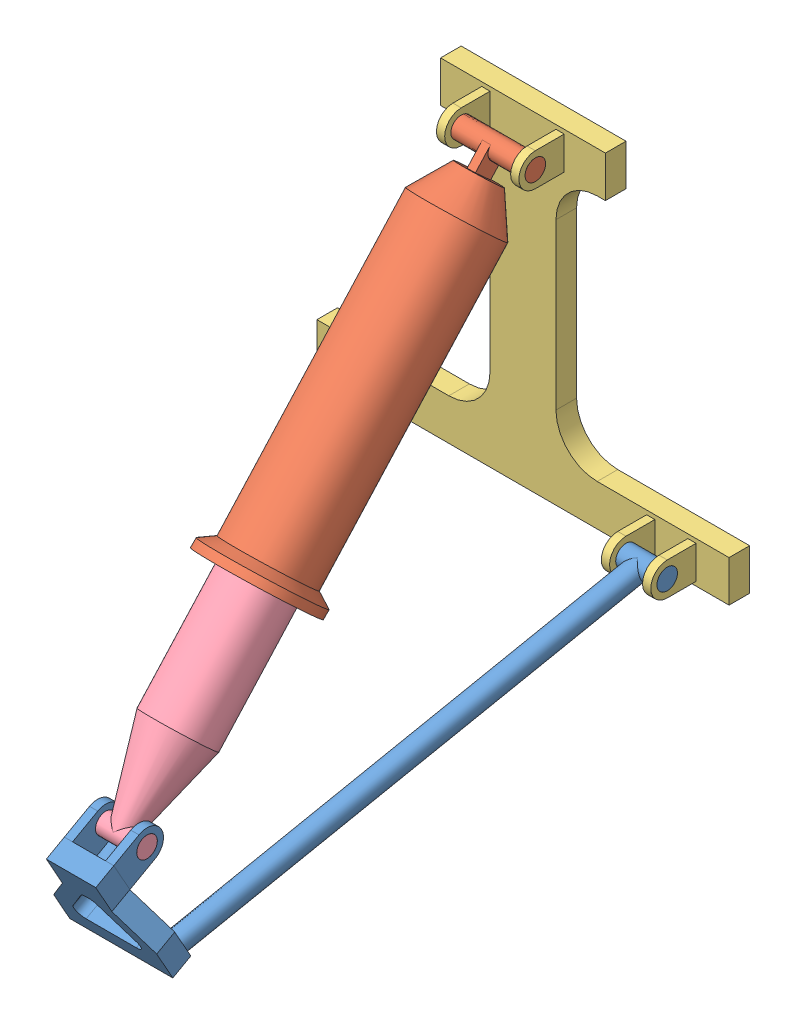
SolidWorks assembly Assembly2_SmithF, configuration 1. Lengths in mm.
Overall size (100 133.96 114.65).
4 component instances, 4 part files, 9 mates.
Components (placement in the parent):
- A-Arm-1: A-Arm [Default<As Machined>] at (0 5 12) x (1 0 0) z (0 -0.487404 0.873176) size (84 25 107.5)
- Cylinder-1: Cylinder [Default] at (0 11.7553 69.5357) x (1 0 0) z (0 0.672932 0.739705) size (26 88 26)
- Mount-1: Mount [Default] at origin size (100 80 16)
- Piston-1: Piston [Default] at (0 12.8104 68.5758) x (1 0 0) z (0 -0.739705 0.672932) size (16 16 102.5)
Mates (geometry in assembly coordinates):
- Coincident1: coordinate: point of Mount-1
- Concentric1: concentric anti-aligned: cylinder of Cylinder-1 through (13 75 12) axis (-1 0 0) radius 2.5; cylinder of Mount-1 through (-50 75 12) axis (1 0 0) radius 2.5
- Coincident2: coincident aligned: plane of Cylinder-1 through (10 11.7553 69.5357) normal (1 0 0); plane of Mount-1 through (10 79 17) normal (1 0 0)
- Concentric2: concentric anti-aligned: cylinder of Cylinder-1 through (0 70.9316 15.7011) axis (0 0.739705 -0.672932) radius 8; cylinder of Piston-1 through (0 -24.1748 102.2224) axis (0 -0.739705 0.672932) radius 8
- Parallel1: parallel aligned: plane of Cylinder-1 through (10 11.7553 69.5357) normal (1 0 0); plane of Piston-1 through (6 -24.1748 102.2224) normal (1 0 0)
- Concentric3: concentric anti-aligned: cylinder of A-Arm-1 through (42 5 12) axis (-1 0 0) radius 2.5; cylinder of Mount-1 through (-50 5 12) axis (1 0 0) radius 2.5
- Coincident4: coincident aligned: plane of A-Arm-1 through (42 5 12) normal (1 0 0); plane of Mount-1 through (42 9 17) normal (1 0 0)
- Concentric4: concentric aligned: cylinder of A-Arm-1 through (-42 -24.1748 102.2224) axis (1 0 0) radius 2.5; cylinder of Piston-1 through (-6 -24.1748 102.2224) axis (1 0 0) radius 2.5
- Distance2: distance = 20 mm anti-aligned: plane of Cylinder-1 through (0 69.9732 27.3882) normal (0 -0.739705 0.672932); plane of Piston-1 through (0 49.7956 34.9292) normal (0 0.739705 -0.672932)
